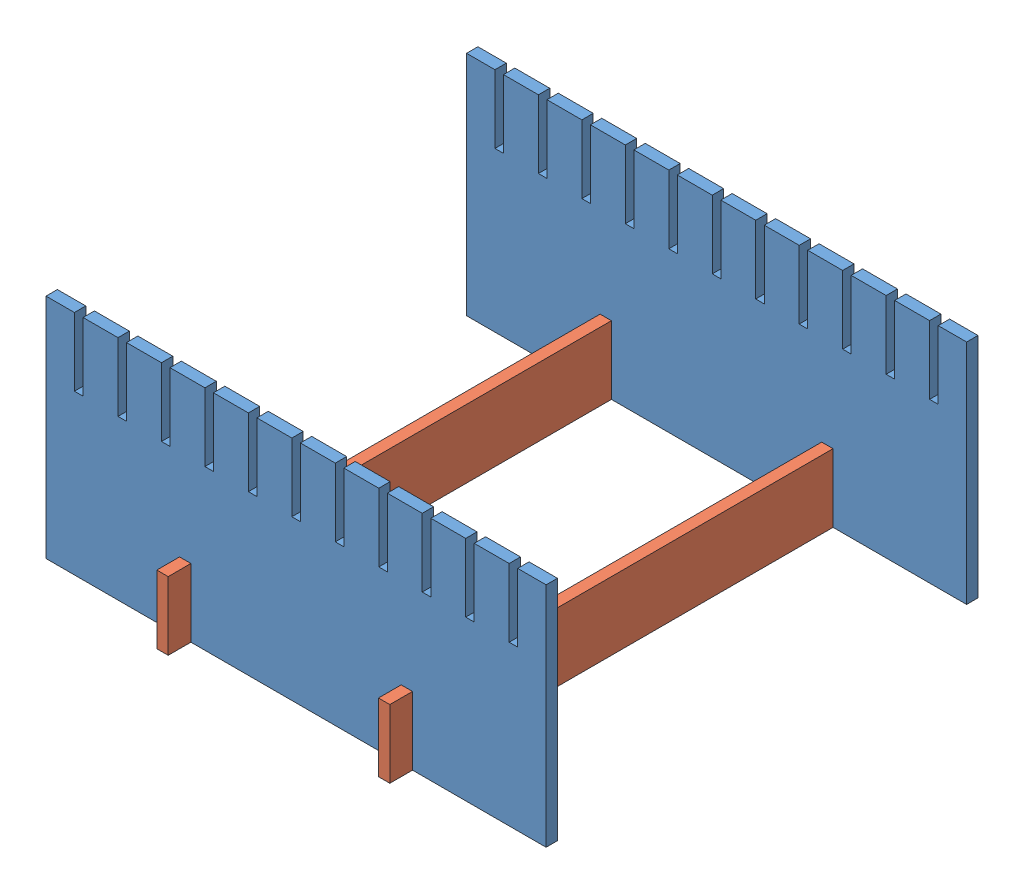
SolidWorks assembly GE-19186, configuration Default. Lengths in mm.
Overall size (558.8 254 533.4).
4 component instances, 2 part files, 9 mates.
Components (placement in the parent):
- GE-19186-02-1: GE-19186-02 [Default] at (395.7526 168.3483 467.8788) x (-1 0 0) z (0 -1 0) size (558.8 12.7 254)
- GE-19186-02-2: GE-19186-02 [Default] at (-163.0474 168.3483 -14.7212) x (1 0 0) z (0 -1 0) size (558.8 12.7 254)
- GE-19186-01-3: GE-19186-01 [Default] at (-7.4724 206.4483 -40.1212) size (12.7 76.2 533.4)
- GE-19186-01-4: GE-19186-01 [Default] at (240.1776 206.4483 -40.1212) size (12.7 76.2 533.4)
Mates (geometry in assembly coordinates):
- Coincident16: coincident: plane of GE-19186-02-1 through (395.7526 219.1483 455.1788) normal (0 -1 0); plane of GE-19186-01-4 through (233.8276 219.1483 467.8788) normal (0 1 0)
- Coincident22: coincident: plane of GE-19186-02-1 through (395.7526 168.3483 455.1788) normal (0 0 -1); plane of GE-19186-01-4 through (233.8276 244.5483 455.1788) normal (0 0 1)
- Coincident23: coincident: plane of GE-19186-02-1 through (246.5276 168.3483 455.1788) normal (-1 0 0); plane of GE-19186-01-4 through (246.5276 168.3483 493.2788) normal (1 0 0)
- Coincident24: coincident: plane of assembly; plane of assembly; plane of GE-19186-02-2 through (-163.0474 168.3483 -2.0212) normal (0 0 1); plane of GE-19186-01-4 through (233.8276 244.5483 -2.0212) normal (0 0 -1)
- Coincident25: coincident: plane of assembly; plane of assembly; plane of GE-19186-02-2 through (-163.0474 219.1483 -2.0212) normal (0 -1 0); plane of GE-19186-01-4 through (233.8276 219.1483 -14.7212) normal (0 1 0)
- Coincident26: coincident: plane of assembly; plane of assembly; plane of GE-19186-02-2 through (246.5276 168.3483 -2.0212) normal (-1 0 0); plane of GE-19186-01-4 through (246.5276 168.3483 493.2788) normal (1 0 0)
- Coincident27: coincident: plane of assembly; plane of assembly; plane of GE-19186-02-2 through (-163.0474 219.1483 -2.0212) normal (0 -1 0); plane of GE-19186-01-3 through (-13.8224 219.1483 -14.7212) normal (0 1 0)
- Coincident28: coincident: plane of assembly; plane of assembly; plane of GE-19186-02-2 through (-13.8224 168.3483 -2.0212) normal (1 0 0); plane of GE-19186-01-3 through (-13.8224 168.3483 493.2788) normal (-1 0 0)
- Coincident29: coincident: plane of assembly; plane of assembly; plane of GE-19186-02-2 through (-163.0474 168.3483 -2.0212) normal (0 0 1); plane of GE-19186-01-3 through (-13.8224 244.5483 -2.0212) normal (0 0 -1)
